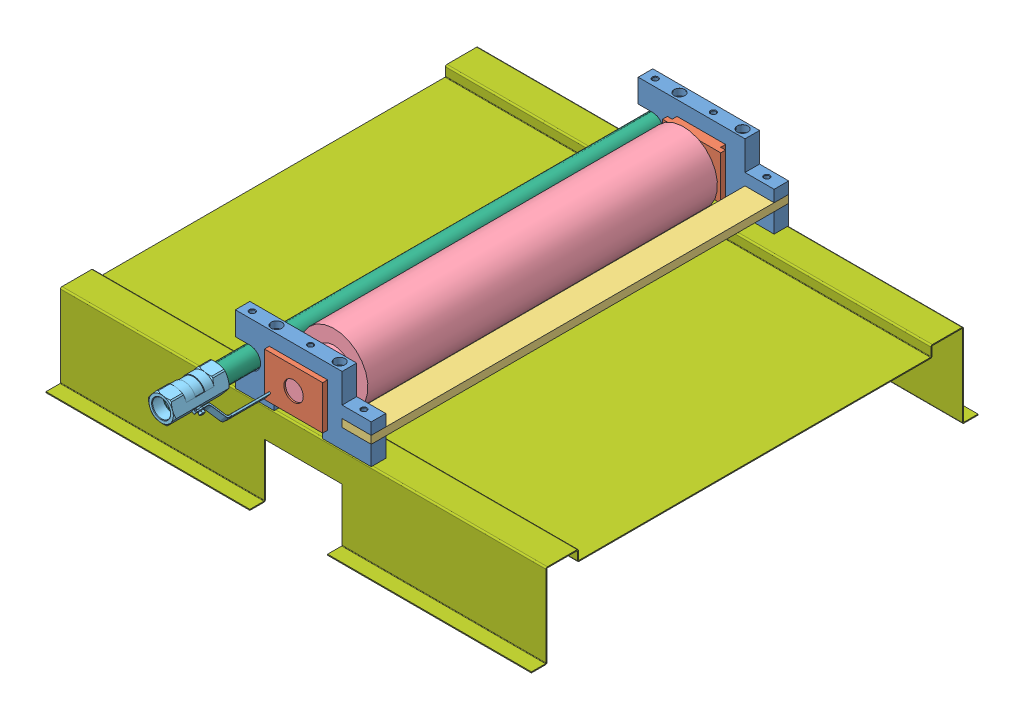
SolidWorks assembly 滚筒部分, configuration 默认. Lengths in mm.
Overall size (500 167.15 536.4).
9 component instances, 7 part files, 17 mates.
Components (placement in the parent):
- 滚筒部分-连接块1-1: 滚筒部分-连接块1 [默认] at (0 0 14.2303) size (140 70 15)
- 滚筒部分-连接块2-1: 滚筒部分-连接块2 [默认] at (-5 -2.5 9.2303) x (-1 0 0) z (0 0 1) size (60 45 30)
- 滚筒部分-连接块3-1: 滚筒部分-连接块3 [默认] at (55 -11 14.2303) size (30 8 430)
- 滚筒-1: 滚筒 [默认] at (-5 -2.5 227.5817) x (0 0 -1) z (-0.851897 -0.523709 0) size (440 70 70)
- 滚筒部分-连接块1-2: 滚筒部分-连接块1 [默认] at (0 0 429.2303) size (140 70 15)
- 滚筒部分-连接块2-2: 滚筒部分-连接块2 [默认] at (-5 -2.5 419.2303) x (-1 0 0) z (0 0 1) size (60 45 30)
- 一片式内螺纹球阀[DN15]-1: 一片式内螺纹球阀[DN15] [DN15] at (-55 0 507.1303) x (0 0 -1) z (-0.641063 -0.767488 0) size (116.5 43.57 28.16)
- 水管-1: 水管 [默认] at (-55 0 14.2303) x (-0.830643 -0.556806 0) z (-0.556806 0.830643 0) size (20 510 20)
- 支撑架-1: 支撑架 [默认] at (0 -45.5 229.2303) x (0 0 -1) z (1 0 0) size (460 86.5 500)
Mates (geometry in assembly coordinates):
- 重合1: coincident anti-aligned: plane of 零件2^滚筒部分-1 through (40 -15 29.2303) normal (0 1 0); plane of 零件3^滚筒部分-1 through (40 -15 444.2303) normal (0 -1 0)
- 重合2: coincident aligned: plane of 零件2^滚筒部分-1 through (-55 0 14.2303) normal (0 0 -1); plane of 零件3^滚筒部分-1 through (55 -11 14.2303) normal (0 0 -1)
- 重合3: coincident aligned: plane of 零件2^滚筒部分-1 through (70 -15 29.2303) normal (1 0 0); plane of 零件3^滚筒部分-1 through (70 -7 444.2303) normal (1 0 0)
- 重合6: coincident anti-aligned: plane of 零件2^滚筒部分-1 through (-30 20 29.2303) normal (0 -1 0); plane of 零件1^滚筒部分-1 through (25 20 39.2303) normal (0 1 0)
- 重合7: coincident anti-aligned: plane of 零件2^滚筒部分-1 through (-30 -35 29.2303) normal (1 0 0); plane of 零件1^滚筒部分-1 through (-30 55 14.2303) normal (-1 0 0)
- 重合8: coincident anti-aligned: plane of 零件2^滚筒部分-1 through (-55 0 14.2303) normal (0 0 -1); plane of 零件1^滚筒部分-1 through (-45 55 14.2303) normal (0 0 1)
- 同心1: concentric aligned: circle of 零件1^滚筒部分-1; circle of 滚筒-1
- 重合9: coincident aligned: plane of 滚筒部分-连接块1-1 through (-70 -35 29.2303) normal (0 -1 0); plane of 滚筒部分-连接块1-2 through (-70 -35 444.2303) normal (0 -1 0)
- 距离1: distance = 430 mm anti-aligned: plane of 滚筒部分-连接块1-2 through (-55 0 444.2303) normal (0 0 1); plane of 滚筒部分-连接块1-1 through (-55 0 14.2303) normal (0 0 -1)
- 重合11: coincident aligned: plane of 滚筒部分-连接块1-1 through (-70 -11 29.2303) normal (-1 0 0); plane of 滚筒部分-连接块1-2 through (-70 35 444.2303) normal (-1 0 0)
- 同心2: concentric anti-aligned: cylinder of 一片式内螺纹球阀[DN15]-1 through (-55 0 535.6303) axis (0 0 1) radius 9.3155; cylinder of 水管-1 through (-55 0 524.2303) axis (0 0 -1) radius 10
- 同心3: concentric aligned: cylinder of 滚筒部分-连接块1-2 through (-55 0 444.2303) axis (0 0 -1) radius 11; cylinder of 水管-1 through (-55 0 524.2303) axis (0 0 -1) radius 10
- 重合12: coincident aligned: plane of 一片式内螺纹球阀[DN15]-1 through (-62.1495 5.9718 524.2303) normal (0 0 1); plane of 水管-1 through (-55 0 524.2303) normal (0 0 1)
- 重合15: coincident anti-aligned: plane of 滚筒部分-连接块1-2 through (20 -35 444.2303) normal (0 -1 0); plane of 支撑架-1 through (0 -35 229.2303) normal (0 1 0)
- 重合16: coincident aligned: plane of 滚筒部分-连接块1-2 through (-55 0 444.2303) normal (0 0 1); plane of 支撑架-1 through (0 -45.5 444.2303) normal (0 0 1)
- 距离2: distance = 180 mm aligned: plane of 滚筒部分-连接块1-2 through (-70 -11 444.2303) normal (-1 0 0); plane of 支撑架-1 through (-250 -35 442.7303) normal (-1 0 0)
- 重合18: coincident aligned: plane of 滚筒部分-连接块1-1 through (-55 0 14.2303) normal (0 0 -1); plane of 水管-1 through (-55 0 14.2303) normal (0 0 -1)
